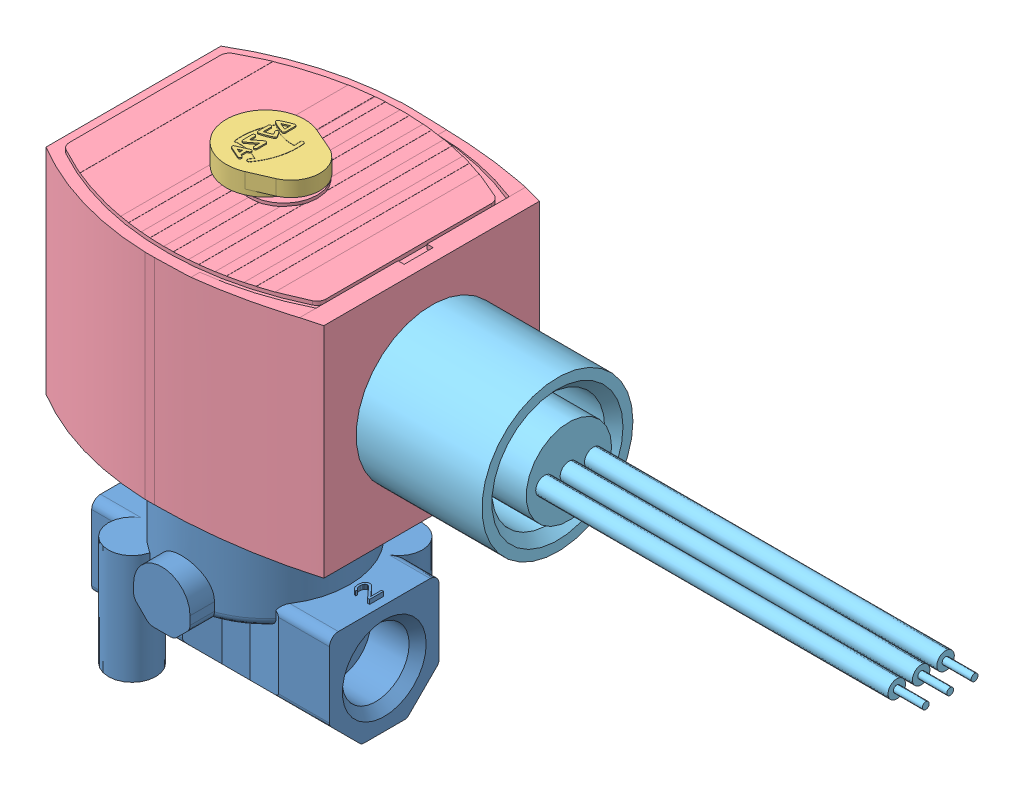
SolidWorks assembly 8262H019VDC12_DCD, configuration Default. Lengths in mm.
Overall size (136.02 75.37 42.93).
5 component instances, 5 part files, 0 mates.
Components (placement in the parent):
- 295525-002M6-1: 295525-002M6 [Default] at origin size (39.61 28.82 32.29)
- 295530-004-1-42_52-1: 295530-004-1-42_52 [Default] at (0 13.8564 0) x (-1 0 0) z (0 0 -1) size (29.33 8.27 25.4)
- 238754-500_30_32-1: 238754-500_30_32 [Default] at (86.1568 55.6164 -0.1884) x (-1 0 0) z (0 0 -1) size (15.58 3.57 13.03)
- 238754-500-1: 238754-500 [Default] at (86.1568 55.9064 -0.1884) x (-1 0 0) z (0 0 -1) size (49.66 36.75 42.93)
- 238754-500_2-1: 238754-500_2 [Default] at (86.1568 55.9364 -0.0942) x (-1 0 0) z (0 0 -1) size (86.36 25.15 25.15)
